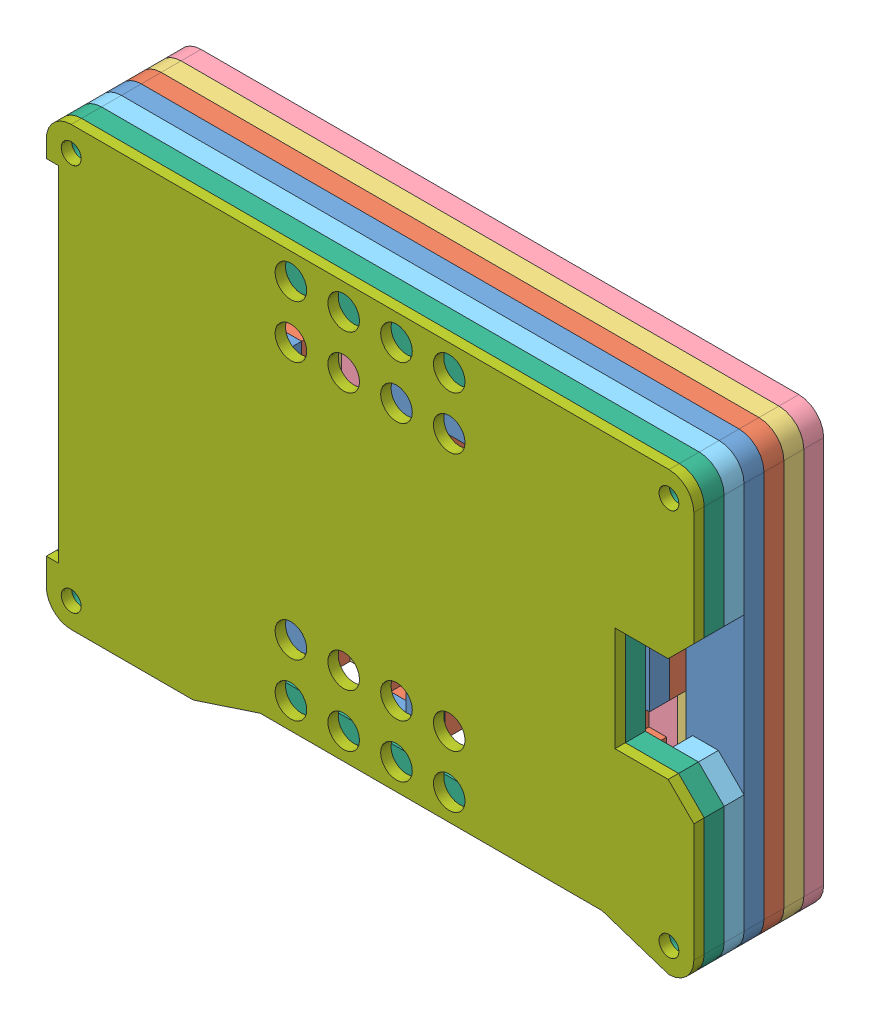
SolidWorks assembly ai_enclosure_rpib+, configuration Default. Lengths in mm.
Overall size (114.87 66.96 19.88).
7 component instances, 7 part files, 20 mates.
Components (placement in the parent):
- ai_enclosure_rpib+_l4-1: ai_enclosure_rpib+_l4 [Layer-2] at (339.8422 -124.2727 8.1718) size (99.11 66.96 3.05)
- ai_enclosure_rpib+_l5-1: ai_enclosure_rpib+_l5 [Default] at origin size (99.11 66.96 3.05)
- ai_enclosure_rpib+_l6-1: ai_enclosure_rpib+_l6 [Default] at (0 0 5.1238) x (-1 0 0) z (0 0 -1) size (99.11 66.96 3.05)
- ai_enclosure_rpib+_l7-1: ai_enclosure_rpib+_l7 [Default] at (0 0 2.0758) x (-1 0 0) z (0 0 -1) size (99.11 66.96 3.05)
- ai_enclosure_rpib+_l3-1: ai_enclosure_rpib+_l3 [Default] at (339.8422 -124.2727 11.2198) size (99.11 66.96 3.05)
- ai_enclosure_rpib+_l2-1: ai_enclosure_rpib+_l2 [Default] at (339.8422 -124.2727 14.2678) size (99.11 66.96 3.05)
- ai_enclosure_rpib+_l1-1: ai_enclosure_rpib+_l1 [Default] at (339.8422 -124.2727 17.3158) size (99.11 66.96 1.59)
Mates (geometry in assembly coordinates):
- InPlace1: in place: plane of ai_enclosure_rpib+_l5-1 through (-57.405 -32.641 5.1238) normal (0 0 -1); plane of ai_enclosure_rpib+_l6-1 through (0 0 5.1238) normal (0 0 -1); moOrthogonalPlaneRef_w of ai_enclosure_rpib+_l5-1 through (-57.405 -32.641 5.1238) normal (0 0 -1); unknown of ai_enclosure_rpib+_l6-1; plane of ai_enclosure_rpib+_l5-1 through (-57.405 -32.641 5.1238) normal (0 0 -1); plane of ai_enclosure_rpib+_l6-1 through (0 0 5.1238) normal (-1 0 0); plane of ai_enclosure_rpib+_l5-1 through (-57.405 -32.641 5.1238) normal (0 0 -1); unknown of ai_enclosure_rpib+_l6-1
- Coincident1: coincident aligned: plane of ai_enclosure_rpib+_l5-1; plane of ai_enclosure_rpib+_l6-1
- Coincident2: coincident aligned: moOrthogonalPlaneRef_w of ai_enclosure_rpib+_l5-1 through (0 0 5.1238) normal (0 1 0); plane of ai_enclosure_rpib+_l6-1
- Coincident3: coincident anti-aligned: moOrthogonalPlaneRef_w of ai_enclosure_rpib+_l5-1 through (0 0 5.1238) normal (1 0 0); plane of ai_enclosure_rpib+_l6-1 through (0 0 5.1238) normal (-1 0 0)
- InPlace2: in place: plane of ai_enclosure_rpib+_l6-1 through (-57.4049 26.6977 2.0758) normal (0 0 -1); plane of ai_enclosure_rpib+_l7-1 through (0 0 2.0758) normal (0 0 -1); plane of ai_enclosure_rpib+_l6-1 through (-57.4049 26.6977 2.0758) normal (0 0 -1); unknown of ai_enclosure_rpib+_l7-1; plane of ai_enclosure_rpib+_l6-1 through (-57.4049 26.6977 2.0758) normal (0 0 -1); plane of ai_enclosure_rpib+_l7-1 through (0 0 2.0758) normal (-1 0 0); plane of ai_enclosure_rpib+_l6-1 through (-57.405 -32.641 2.0758) normal (0 0 -1); unknown of ai_enclosure_rpib+_l7-1
- Coincident4: coincident aligned: plane of ai_enclosure_rpib+_l6-1; plane of ai_enclosure_rpib+_l7-1
- Coincident5: coincident aligned: moOrthogonalPlaneRef_w of ai_enclosure_rpib+_l6-1 through (0 0 2.0758) normal (0 1 0); plane of ai_enclosure_rpib+_l7-1
- Coincident6: coincident anti-aligned: moOrthogonalPlaneRef_w of ai_enclosure_rpib+_l6-1 through (0 0 2.0758) normal (1 0 0); plane of ai_enclosure_rpib+_l7-1 through (0 0 2.0758) normal (-1 0 0)
- InPlace3: in place: plane of ai_enclosure_rpib+_l4-1 through (339.8422 -124.2727 11.2198) normal (0 0 1); plane of ? through (0 0 11.2198) normal (0 0 1); plane of ai_enclosure_rpib+_l4-1 through (339.8422 -124.2727 11.2198) normal (0 0 1); plane of ? through (0 0 11.2198) normal (0 1 0); plane of ai_enclosure_rpib+_l4-1 through (339.8422 -124.2727 11.2198) normal (0 0 1); plane of ? through (0 0 11.2198) normal (1 0 0); plane of ai_enclosure_rpib+_l4-1 through (339.8422 -124.2727 11.2198) normal (0 0 1); unknown of ai_enclosure_rpib+_l3-1
- Coincident7: coincident aligned: plane of ai_enclosure_rpib+_l4-1; plane of ai_enclosure_rpib+_l3-1
- Coincident8: coincident aligned: moOrthogonalPlaneRef_w of ai_enclosure_rpib+_l4-1 through (339.8422 -124.2727 11.2198) normal (0 1 0); plane of ai_enclosure_rpib+_l3-1 through (339.8422 -124.2727 11.2198) normal (0 1 0)
- Coincident9: coincident anti-aligned: moOrthogonalPlaneRef_w of ai_enclosure_rpib+_l4-1 through (339.8422 -124.2727 11.2198) normal (-1 0 0); plane of ai_enclosure_rpib+_l3-1 through (339.8422 -124.2727 11.2198) normal (1 0 0)
- InPlace4: in place: plane of ai_enclosure_rpib+_l3-1 through (339.8422 -124.2727 14.2678) normal (0 0 1); plane of ? through (0 0 14.2678) normal (0 0 1); plane of ai_enclosure_rpib+_l3-1 through (339.8422 -124.2727 14.2678) normal (0 0 1); plane of ? through (0 0 14.2678) normal (0 1 0); plane of ai_enclosure_rpib+_l3-1 through (339.8422 -124.2727 14.2678) normal (0 0 1); plane of ? through (0 0 14.2678) normal (1 0 0); plane of ai_enclosure_rpib+_l3-1 through (339.8422 -124.2727 14.2678) normal (0 0 1); unknown of ai_enclosure_rpib+_l2-1
- Coincident10: coincident aligned: plane of ai_enclosure_rpib+_l3-1; plane of ai_enclosure_rpib+_l2-1
- Coincident11: coincident aligned: moOrthogonalPlaneRef_w of ai_enclosure_rpib+_l3-1 through (339.8422 -124.2727 14.2678) normal (0 1 0); plane of ai_enclosure_rpib+_l2-1 through (339.8422 -124.2727 14.2678) normal (0 1 0)
- Coincident12: coincident anti-aligned: moOrthogonalPlaneRef_w of ai_enclosure_rpib+_l3-1 through (339.8422 -124.2727 14.2678) normal (-1 0 0); plane of ai_enclosure_rpib+_l2-1 through (339.8422 -124.2727 14.2678) normal (1 0 0)
- InPlace5: in place: plane of ai_enclosure_rpib+_l2-1 through (34.0849 -32.641 17.3158) normal (0 0 1); plane of ? through (0 0 17.3158) normal (0 0 1); plane of ai_enclosure_rpib+_l2-1 through (34.0849 -32.641 17.3158) normal (0 0 1); plane of ? through (0 0 17.3158) normal (0 1 0); plane of ai_enclosure_rpib+_l2-1 through (34.0849 -32.641 17.3158) normal (0 0 1); plane of ? through (0 0 17.3158) normal (1 0 0); plane of ai_enclosure_rpib+_l2-1 through (34.0849 -32.641 17.3158) normal (0 0 1); unknown of ai_enclosure_rpib+_l1-1
- Coincident1: coincident aligned: plane of ai_enclosure_rpib+_l2-1; plane of ai_enclosure_rpib+_l1-1
- Coincident2: coincident aligned: moOrthogonalPlaneRef_w of ai_enclosure_rpib+_l2-1 through (339.8422 -124.2727 17.3158) normal (0 1 0); plane of ai_enclosure_rpib+_l1-1 through (339.8422 -124.2727 17.3158) normal (0 1 0)
- Coincident3: coincident anti-aligned: moOrthogonalPlaneRef_w of ai_enclosure_rpib+_l2-1 through (339.8422 -124.2727 17.3158) normal (-1 0 0); plane of ai_enclosure_rpib+_l1-1 through (339.8422 -124.2727 17.3158) normal (1 0 0)
